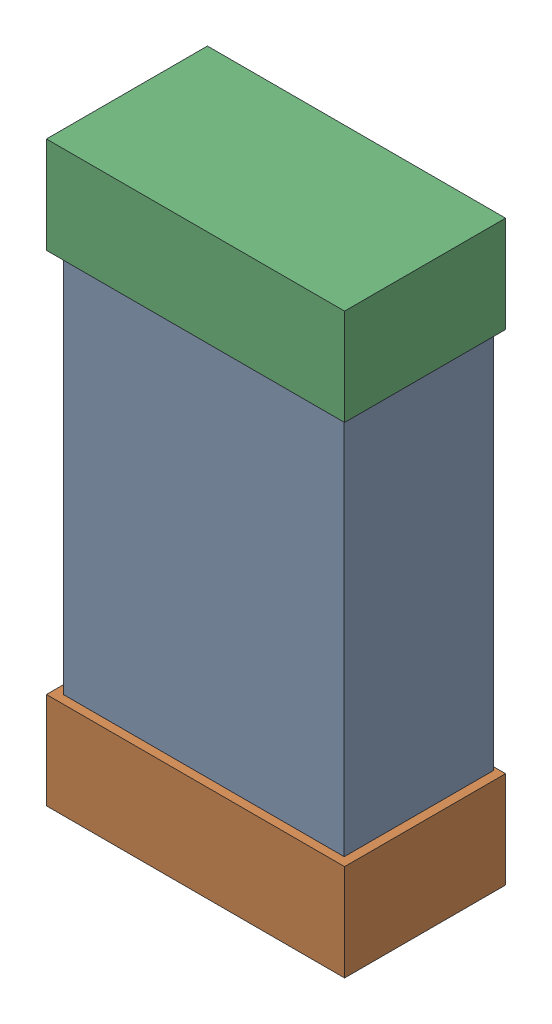
SolidWorks assembly C28, configuration Default. Lengths in mm.
Overall size (0.85 1.65 0.46).
6 component instances, 2 part files, 0 mates.
Components (placement in the parent):
- 432124816_38-1: 432124816_38 [Default] at (19.3001 46.2001 -0.8615) size (0.8 1.5 0.42)
  - Extruded (1)-1: Extruded (1) [Default] at origin size (0.8 1.5 0.42)
- 432138512_76-1: 432138512_76 [Default] at (19.3001 45.5143 -0.8715) size (0.85 0.28 0.46)
  - Extruded-1: Extruded [Default] at origin size (0.85 0.28 0.46)
- 432138512_77-1: 432138512_77 [Default] at (19.3001 46.8858 -0.8715) size (0.85 0.28 0.46)
  - Extruded-1: Extruded [Default] at origin size (0.85 0.28 0.46)
